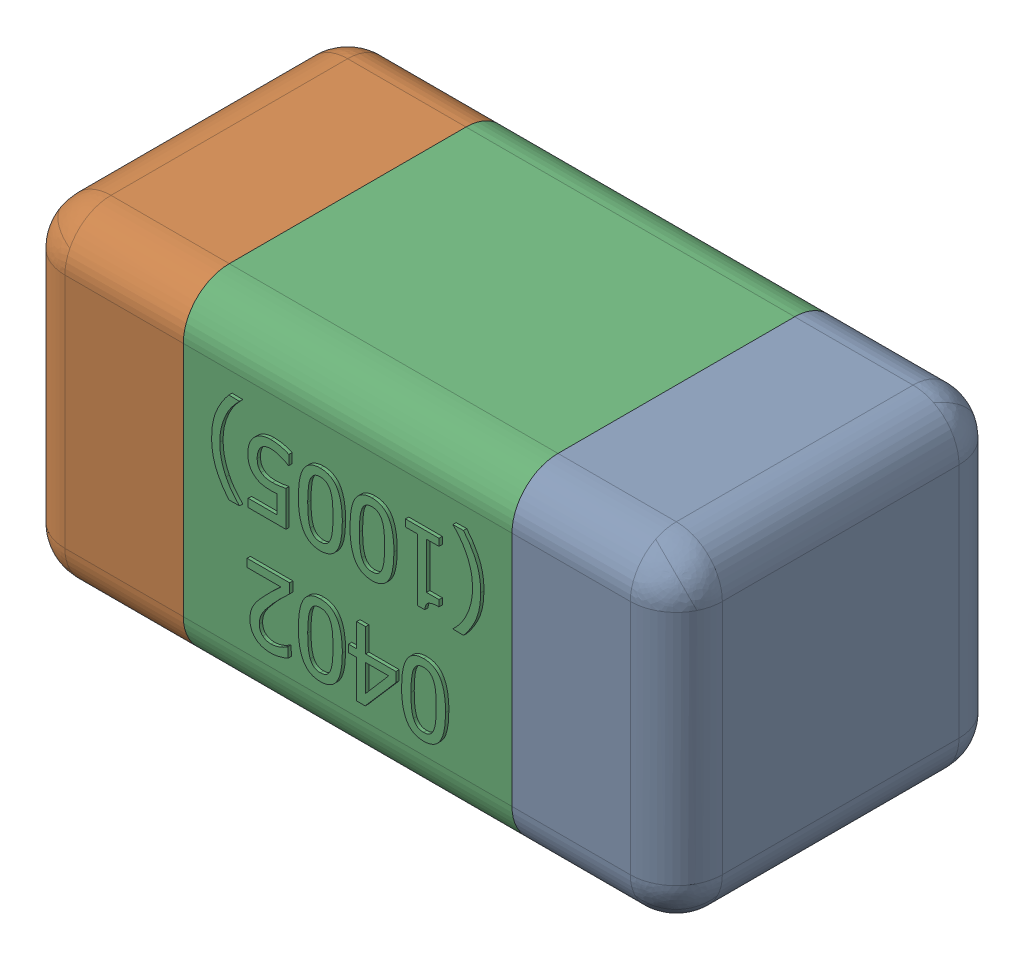
SolidWorks assembly C34, configuration Standard. Lengths in mm.
Overall size (1.01 0.51 0.51).
4 component instances, 3 part files, 0 mates.
Components (placement in the parent):
- C34-subassembly-1-1: C34-subassembly-1 [Standard] at (-7.2001 11.3 0) x (-1 0 0) z (0 0 1) size (1.01 0.51 0.51)
  - User Library-0402_Cap-1: User Library-0402_Cap [Standard] at origin size (0.26 0.51 0.51)
  - User Library-0402_Cap-1-1: User Library-0402_Cap-1 [Standard] at origin size (0.26 0.5 0.51)
  - User Library-0402_Cap-2-1: User Library-0402_Cap-2 [Standard] at origin size (0.5 0.5 0.51)
